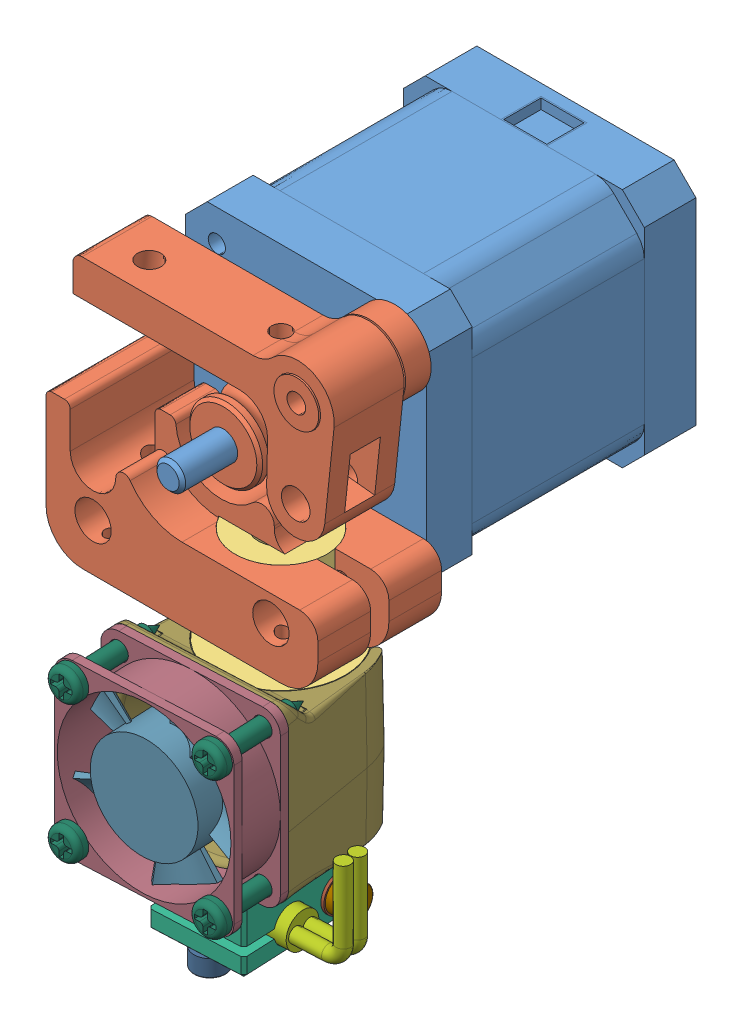
SolidWorks assembly Assem1, configuration Default. Lengths in mm.
Overall size (50.6 95.15 85.45).
20 component instances, 15 part files, 5 mates.
Components (placement in the parent):
- NEMA17_48-1: NEMA17_48 [Default] at (18.8957 36.6231 70.3037) size (42 42 71)
- Alu Extruder-1: Alu Extruder [Default] at (18.8957 36.6231 67.2303) x (0 1 0) z (0 0 1) size (45.54 47.38 21.58)
- E3D All Metal Hotend V6-1: E3D All Metal Hotend V6 [Default] at (25.3587 -17.0769 81.0924) x (-0.045001 0 -0.998987) z (0 -1 0) size (38.16 34.25 62.3)
  - E3D v6 HotEnd - Heatsink-1: E3D v6 HotEnd - Heatsink [Default] at origin size (22.3 22.3 42.7)
  - E3D v6 HotEnd - Heatbreak-1: E3D v6 HotEnd - Heatbreak [Default] at (0 0 7.1) size (7 7 21.9)
  - E3D v6 HotEnd - Nozzle-1: E3D v6 HotEnd - Nozzle [Default] at (0 0 17.6) x (0.866025 0.5 0) z (0 0 1) size (8.08 7 12.5)
  - E3D v6 HotEnd - Heat Block-1: E3D v6 HotEnd - Heat Block [Default] at (-15.5 8 13.6) x (1 0 0) z (0 1 0) size (20 11.5 16)
  - Ceramic Cartridge Heater-1: Ceramic Cartridge Heater [Default] at (-7 10 9.6) x (1 0 0) z (0 1 0) size (6 18 29.25)
  - Thermistor-1: Thermistor [Default] at (2.5 3.65 11.6) x (0.903857 0 0.427835) z (0 -1 0) size (4.52 1.5 4.65)
  - HEXAGON SOCKET HEAD CAP SCREWS_SCB3-4-1: HEXAGON SOCKET HEAD CAP SCREWS_SCB3-4 [Default] at (1 9 8.8) x (0.999538 0 0.030402) z (0 1 0) size (5.5 5.5 7)
  - HEXAGON SOCKET HEAD CAP SCREWS_SCB3-10-1: HEXAGON SOCKET HEAD CAP SCREWS_SCB3-10 [Default] at (-13 0 13.6) size (5.5 5.5 13)
  - Flat Washers_PWF3-1: Flat Washers_PWF3 [Default] at (1 9 8.8) x (1 0 0) z (0 1 0) size (6 6 0.5)
  - E3D-v6 Fan Duct-1: E3D-v6 Fan Duct [Default] x (1 0 0) z (0 1 0) size (22.31 30.04 30)
  - Fan-DC-KDE0503PFB3-Promoco_Fan-DC-KDE0503PFB3-Promoco-1: Fan-DC-KDE0503PFB3-Promoco_Fan-DC-KDE0503PFB3-Promoco [Default] at (-15 0 -15) x (0 0 -1) z (-1 0 0) size (30 30 10)
    - Fan-House-30x30x10-Promoco_Fan-House-KDE0503PFB3-Promoco-1: Fan-House-30x30x10-Promoco_Fan-House-KDE0503PFB3-Promoco [Default] at origin size (30 30 10)
    - Fan-30x30x10-Promoco_Fan-KDE0503PFB3-Promoco-1: Fan-30x30x10-Promoco_Fan-KDE0503PFB3-Promoco [Default] x (0 0 -1) z (-0.999131 0.04169 0) size (8.5 27.91 28)
  - Self Tapping Screws - Pan Head_CSPTRSA-SUS-TP3-16-1: Self Tapping Screws - Pan Head_CSPTRSA-SUS-TP3-16 [Default] at (-25 -12 -27) size (18.01 5.5 5.5)
  - Self Tapping Screws - Pan Head_CSPTRSA-SUS-TP3-16-2: Self Tapping Screws - Pan Head_CSPTRSA-SUS-TP3-16 [Default] at (-25 12 -27) size (18.01 5.5 5.5)
  - Self Tapping Screws - Pan Head_CSPTRSA-SUS-TP3-16-3: Self Tapping Screws - Pan Head_CSPTRSA-SUS-TP3-16 [Default] at (-25 12 -3) size (18.01 5.5 5.5)
  - Self Tapping Screws - Pan Head_CSPTRSA-SUS-TP3-16-4: Self Tapping Screws - Pan Head_CSPTRSA-SUS-TP3-16 [Default] at (-25 -12 -3) size (18.01 5.5 5.5)
Mates (geometry in assembly coordinates):
- Concentric1: concentric anti-aligned: cylinder of NEMA17_48-1 through (34.3957 21.1231 65.8037) axis (0 0 1) radius 1.5; cylinder of Alu Extruder-1 through (34.3957 21.1231 86.801) axis (0 0 -1) radius 1.632
- Concentric2: concentric anti-aligned: cylinder of NEMA17_48-1 through (3.3957 21.1231 65.8037) axis (0 0 1) radius 1.5; cylinder of Alu Extruder-1 through (3.3957 21.1231 86.801) axis (0 0 -1) radius 1.632
- Coincident1: coincident anti-aligned: plane of NEMA17_48-1 through (18.8957 36.6231 70.3037) normal (0 0 1); plane of Alu Extruder-1 through (15.283 21.7439 70.3037) normal (0 0 -1)
- Concentric3: concentric aligned: cylinder of Alu Extruder-1 through (25.3587 12.9331 81.0924) axis (0 1 0) radius 8.001; cylinder of E3D All Metal Hotend V6-1/E3D v6 HotEnd - Heatsink-1 through (25.3587 25.6231 81.0924) axis (0 1 0) radius 4
- Coincident2: coincident aligned: plane of Alu Extruder-1 through (42.5857 25.6231 74.8503) normal (0 1 0); plane of E3D All Metal Hotend V6-1/E3D v6 HotEnd - Heatsink-1 through (25.3587 25.6231 81.0924) normal (0 1 0)
